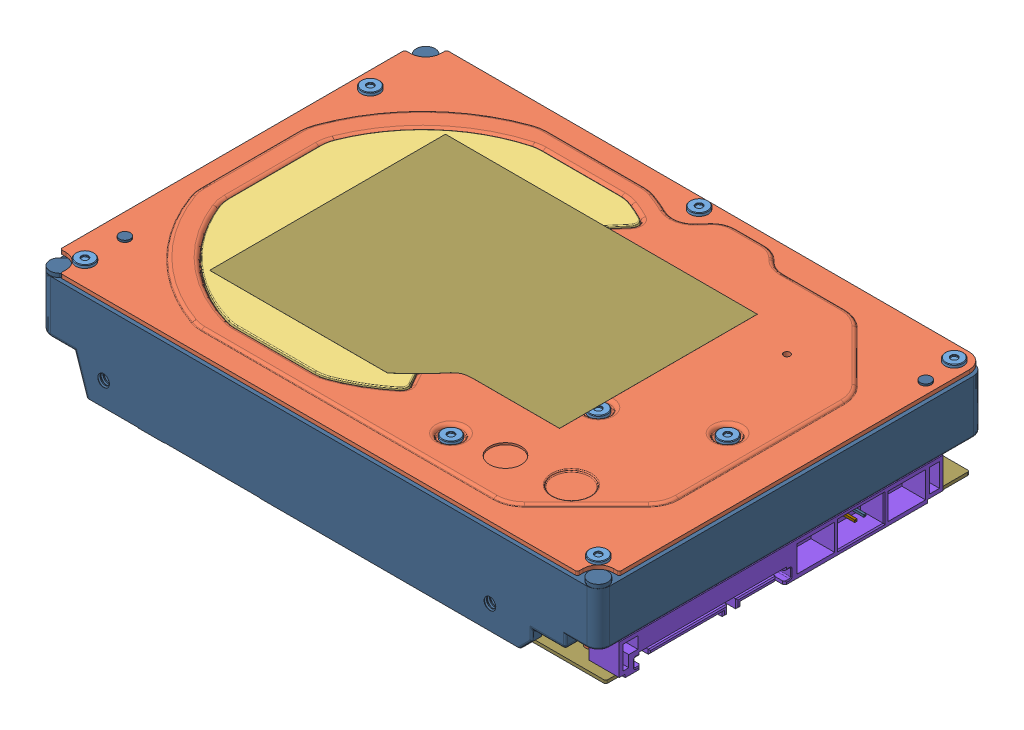
SolidWorks assembly WD101EFAX--WD_Red_Plus_10TB_NAS_HDD, configuration Default. Lengths in mm.
Overall size (147.95 25.84 101.7).
87 component instances, 48 part files, 0 mates.
Components (placement in the parent):
- WD101EFAX--WD_Red_Plus_10TB_NAS_HDD.step-1: WD101EFAX--WD_Red_Plus_10TB_NAS_HDD.step [Default] at origin size (147.95 25.84 101.7)
  - Backplate.step-1: Backplate.step [Default] at origin size (147 10.82 101.6)
    - 90318A102.step-1: 90318A102.step [Default] at (-67.5 0.7937 44.8) x (-1 0 0) z (0 1 0) size (4.76 4.76 10.32)
    - 90318A102.step-2: 90318A102.step [Default] at (-69.25 0.7937 -32) x (-1 0 0) z (0 1 0) size (4.76 4.76 10.32)
    - 90318A102.step-3: 90318A102.step [Default] at (69.5 0.7937 -46.8) x (-1 0 0) z (0 1 0) size (4.76 4.76 10.32)
    - 90318A102.step-4: 90318A102.step [Default] at (1.4 0.7937 -47.8) x (-1 0 0) z (0 1 0) size (4.76 4.76 10.32)
    - 90318A102.step-5: 90318A102.step [Default] at (67.5 0.7937 44.8) x (-1 0 0) z (0 1 0) size (4.76 4.76 10.32)
    - 90318A102.step-6: 90318A102.step [Default] at (56.7 0.2938 0) x (-1 0 0) z (0 1 0) size (4.76 4.76 10.32)
    - 90318A102.step-7: 90318A102.step [Default] at (33.8162 0.2938 11.1162) x (-1 0 0) z (0 1 0) size (4.76 4.76 10.32)
    - 90318A102.step-8: 90318A102.step [Default] at (20.3283 0.2938 36.3717) x (-1 0 0) z (0 1 0) size (4.76 4.76 10.32)
    - Backplate-0.step-1: Backplate-0.step [Default] at origin size (147 1.5 101.6)
    - Backplate-1.step-1: Backplate-1.step [Default] at origin size (66.36 1 80.15)
    - Backplate-2.step-1: Backplate-2.step [Default] at origin size (14 0.5 14)
    - Backplate-3.step-1: Backplate-3.step [Default] at origin size (6 0.5 6)
  - Connector.step-1: Connector.step [Default] at (0 0 -8.755) size (8 8.9 85.2)
    - Male Connector.step-1: Male Connector.step [Default] at (68.6 -22.9 29.435) x (0 0 -1) z (0 -1 0) size (85.2 8 8.9)
      - PIns.step-1: PIns.step [Default] at origin size (32.59 6.5 0.5)
        - Long Pin.step-1: Long Pin.step [Default] at origin size (0.84 6.5 0.5)
        - Short Pin.step-1: Short Pin.step [Default] at origin size (0.84 6 0.5)
        - Long Pin.step-2: Long Pin.step [Default] at (-3.81 0 0) size (0.84 6.5 0.5)
        - Long Pin.step-3: Long Pin.step [Default] at (-7.62 0 0) size (0.84 6.5 0.5)
        - Long Pin.step-4: Long Pin.step [Default] at (-17.78 0 0) size (0.84 6.5 0.5)
        - Long Pin.step-5: Long Pin.step [Default] at (-19.05 0 0) size (0.84 6.5 0.5)
        - Long Pin.step-6: Long Pin.step [Default] at (-20.32 0 0) size (0.84 6.5 0.5)
        - Long Pin.step-7: Long Pin.step [Default] at (-25.4 0 0) size (0.84 6.5 0.5)
        - Long Pin.step-8: Long Pin.step [Default] at (-26.67 0 0) size (0.84 6.5 0.5)
        - Long Pin.step-9: Long Pin.step [Default] at (-27.94 0 0) size (0.84 6.5 0.5)
        - Short Pin.step-2: Short Pin.step [Default] at (-1.27 0 0) size (0.84 6 0.5)
        - Short Pin.step-3: Short Pin.step [Default] at (-3.81 0 0) size (0.84 6 0.5)
        - Short Pin.step-4: Short Pin.step [Default] at (-5.08 0 0) size (0.84 6 0.5)
        - Short Pin.step-5: Short Pin.step [Default] at (-12.7 0 0) size (0.84 6 0.5)
        - Short Pin.step-6: Short Pin.step [Default] at (-13.97 0 0) size (0.84 6 0.5)
        - Short Pin.step-7: Short Pin.step [Default] at (-15.24 0 0) size (0.84 6 0.5)
        - Short Pin.step-8: Short Pin.step [Default] at (-20.32 0 0) size (0.84 6 0.5)
        - Short Pin.step-9: Short Pin.step [Default] at (-21.59 0 0) size (0.84 6 0.5)
        - Short Pin.step-10: Short Pin.step [Default] at (-22.86 0 0) size (0.84 6 0.5)
        - Short Pin.step-11: Short Pin.step [Default] at (-27.94 0 0) size (0.84 6 0.5)
        - Short Pin.step-12: Short Pin.step [Default] at (-29.21 0 0) size (0.84 6 0.5)
        - Short Pin.step-13: Short Pin.step [Default] at (-30.48 0 0) size (0.84 6 0.5)
      - Male Connector-4.step-1: Male Connector-4.step [Default] at origin size (85.2 8 8.9)
    - Connector-5.step-1: Connector-5.step [Default] at origin size (8 0.6 0.6)
    - Connector-6.step-1: Connector-6.step [Default] at origin size (8 0.6 0.6)
  - PCB.step-1: PCB.step [Default] at origin size (80.83 3.18 95.6)
    - Screws.step-1: Screws.step [Default] at origin size (71.7 3.18 87.63)
      - 92703A100.step-1: 92703A100.step [Default] at (-1.1836 -24.92 31.6536) x (1 0 0) z (0 -1 0) size (4.11 4.11 3.18)
      - 92703A100.step-2: 92703A100.step [Default] at (62.3131 -24.92 41.6536) x (1 0 0) z (0 -1 0) size (4.11 4.11 3.18)
      - 92703A100.step-3: 92703A100.step [Default] at (62.3534 -24.92 -36.6535) x (1 0 0) z (0 -1 0) size (4.11 4.11 3.18)
      - 92703A100.step-4: 92703A100.step [Default] at (41.3534 -24.92 -15.6535) x (1 0 0) z (0 -1 0) size (4.11 4.11 3.18)
      - 92703A100.step-5: 92703A100.step [Default] at (4.7637 -24.92 -41.8643) x (1 0 0) z (0 -1 0) size (4.11 4.11 3.18)
      - 92703A100.step-6: 92703A100.step [Default] at (-5.2363 -24.92 -28.8643) x (1 0 0) z (0 -1 0) size (4.11 4.11 3.18)
    - PCB-7.step-1: PCB-7.step [Default] at origin size (80.83 0.8 95.6)
    - PCB-8.step-1: PCB-8.step [Default] at origin size (5 0.01 5)
    - PCB-9.step-1: PCB-9.step [Default] at origin size (2 0.01 2)
    - PCB-10.step-1: PCB-10.step [Default] at origin size (2 0.01 2)
    - PCB-11.step-1: PCB-11.step [Default] at origin size (1 0.01 1)
    - PCB-12.step-1: PCB-12.step [Default] at origin size (1 0.01 1)
    - PCB-13.step-1: PCB-13.step [Default] at origin size (1 0.01 1)
    - PCB-14.step-1: PCB-14.step [Default] at origin size (1 0.01 1)
    - PCB-15.step-1: PCB-15.step [Default] at origin size (1 0.01 1)
    - PCB-16.step-1: PCB-16.step [Default] at origin size (1 0.01 1)
    - PCB-17.step-1: PCB-17.step [Default] at origin size (1 0.01 1)
    - PCB-18.step-1: PCB-18.step [Default] at origin size (1 0.01 1)
    - PCB-19.step-1: PCB-19.step [Default] at origin size (1 0.01 1)
    - PCB-20.step-1: PCB-20.step [Default] at origin size (1 0.01 1)
    - PCB-21.step-1: PCB-21.step [Default] at origin size (5.5 0.01 2)
    - PCB-22.step-1: PCB-22.step [Default] at origin size (2 0.01 2)
    - PCB-23.step-1: PCB-23.step [Default] at origin size (5 0.01 5)
    - PCB-24.step-1: PCB-24.step [Default] at origin size (5 0.01 5)
    - PCB-25.step-1: PCB-25.step [Default] at origin size (5 0.01 5)
    - PCB-26.step-1: PCB-26.step [Default] at origin size (2 0.01 2)
    - PCB-27.step-1: PCB-27.step [Default] at origin size (1 0.01 1)
    - PCB-28.step-1: PCB-28.step [Default] at origin size (1 0.01 1)
    - PCB-29.step-1: PCB-29.step [Default] at origin size (1 0.01 1)
    - PCB-30.step-1: PCB-30.step [Default] at origin size (1 0.01 1)
    - PCB-31.step-1: PCB-31.step [Default] at origin size (1 0.01 1)
    - PCB-32.step-1: PCB-32.step [Default] at origin size (1 0.01 1)
    - PCB-33.step-1: PCB-33.step [Default] at origin size (1 0.01 1)
    - PCB-34.step-1: PCB-34.step [Default] at origin size (1 0.01 1)
    - PCB-35.step-1: PCB-35.step [Default] at origin size (1 0.01 1)
    - PCB-36.step-1: PCB-36.step [Default] at origin size (1 0.01 1)
    - PCB-37.step-1: PCB-37.step [Default] at origin size (1 0.01 1)
    - PCB-38.step-1: PCB-38.step [Default] at origin size (2 0.01 2)
    - PCB-39.step-1: PCB-39.step [Default] at origin size (5 0.01 5)
    - PCB-40.step-1: PCB-40.step [Default] at origin size (5 0.01 5)
  - Body.step-1: Body.step [Default] at origin size (147.95 25.55 101.7)
  - Ribbon Cable.step-1: Ribbon Cable.step [Default] at origin size (22.58 2.19 28.77)
  - Label.step-1: Label.step [Default] at origin size (82 0.01 62)
